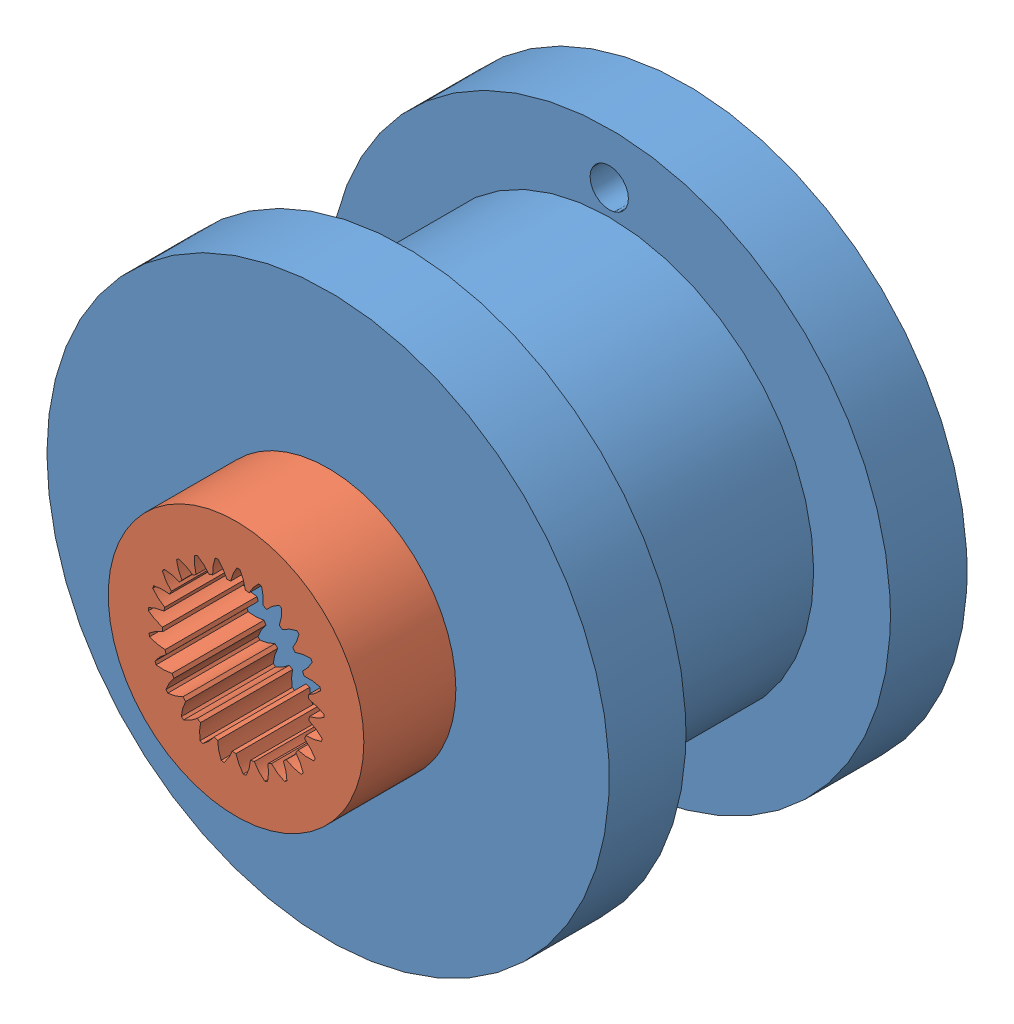
SolidWorks assembly Assem1, configuration Default. Lengths in mm.
Overall size (22 22 17.6).
2 component instances, 2 part files, 2 mates.
Components (placement in the parent):
- pully15_1-1: pully15_1 [Default] at (10.1874 11.9152 8.5493) size (22 22 14)
- p17-1: p17 [Default] at (9.8449 10.7587 23.3891) x (0 0 -1) z (0.862907 -0.505363 0) size (3.6 10 10)
Mates (geometry in assembly coordinates):
- Coincident1: coincident: plane of pully15_1-1 through (10.1874 11.9152 22.5493) normal (0 0 1); plane of p17-1 through (10.1874 11.9152 22.5493) normal (0 0 -1)
- Concentric1: concentric anti-aligned: cylinder of pully15_1-1 through (10.1874 11.9152 8.5493) axis (0 0 1) radius 1.55; cylinder of p17-1 through (10.1874 11.9152 26.1493) axis (0 0 -1) radius 5
